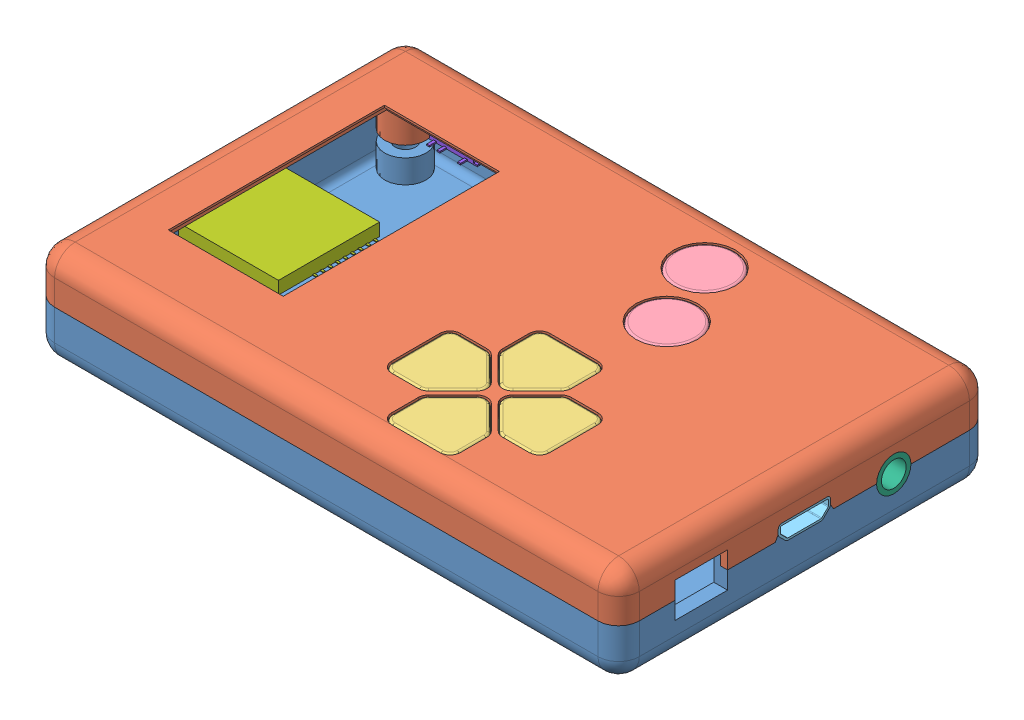
SolidWorks assembly ArduMan, configuration 默认. Lengths in mm.
Overall size (85.3 14.2 54.3).
13 component instances, 8 part files, 24 mates.
Components (placement in the parent):
- ArduMan-bottom-2: ArduMan-bottom [默认] at origin size (85 9.5 54)
- ArduMan-top-3: ArduMan-top [默认] at (0 7.5 0) size (85 7.2 54)
- ArduMan-DPadKey-1: ArduMan-DPadKey [默认] at (4.5 11.2 12.5) size (10.98 3 10.6)
- ArduMan-ABKey-2: ArduMan-ABKey [默认] at (13.5 11.2 -9) size (10 3 10)
- ArduMan-DPadKey-2: ArduMan-DPadKey [默认] at (10 11.2 18) x (0 0 -1) z (1 0 0) size (10.98 3 10.6)
- ArduMan-DPadKey-3: ArduMan-DPadKey [默认] at (15.5 11.2 12.5) x (-1 0 0) z (0 0 -1) size (10.98 3 10.6)
- ArduMan-DPadKey-4: ArduMan-DPadKey [默认] at (10 11.2 7) x (0 0 1) z (-1 0 0) size (10.98 3 10.6)
- ArduMan-ABKey-3: ArduMan-ABKey [默认] at (9.5 11.2 -18.5) x (-1 0 0) z (0 0 -1) size (10 3 10)
- USBMicroF-1: USBMicroF [默认] at (37.44 6.85 0) x (0 0 -1) z (1 0 0) size (7.6 3.5 5.06)
- PJ-313D-1: PJ-313D [默认] at (40 5 -13) x (0 0 -1) z (1 0 0) size (8.4 5.5 14)
- HY-TF1007B-2: HY-TF1007B [默认] at (-25.4 6.85 -6.15) x (0 0 1) z (-1 0 0) size (14.7 2.47 17.6)
- MSK-1103_W13-1: MSK-1103_W13 [默认] at (-38.925 6.85 15.5) x (-1 0 0) z (0 0 -1) size (6.25 1.9 7.8)
- MSK-1103_W13-2: MSK-1103_W13 [默认] at (-31 6.85 -23.425) x (0 0 -1) z (1 0 0) size (6.25 1.9 7.8)
Mates (geometry in assembly coordinates):
- 重合1: coincident anti-aligned: plane of ArduMan-bottom-2 through (0 7.5 0) normal (0 1 0); plane of ArduMan-top-3 through (0 7.5 0) normal (0 -1 0)
- 重合2: coincident aligned: plane of ArduMan-bottom-2 through (-42.5 7.5 27) normal (0 0 1); plane of ArduMan-top-3 through (-42.5 14.2 27) normal (0 0 1)
- 重合3: coincident aligned: plane of ArduMan-bottom-2 through (42.5 7.5 -27) normal (1 0 0); plane of ArduMan-top-3 through (42.5 14.2 -27) normal (1 0 0)
- 重合19: coincident anti-aligned: plane of ArduMan-top-3 through (0 12.2 0) normal (0 -1 0); plane of ArduMan-DPadKey-1 through (0 12.2 16) normal (0 1 0)
- 平行5: parallel aligned: line of ArduMan-top-3 through (-1.5 14.2 9) axis (0 0 1); line of ArduMan-DPadKey-1 through (-1 14.2 9) axis (0 0 1)
- 重合16: coincident aligned: line of ArduMan-top-3 through (4.5 17.4725 12.5) axis (0 -1 0); line of ArduMan-DPadKey-1 through (4.5 14.0504 12.5) axis (0 -1 0)
- 重合22: coincident anti-aligned: plane of ArduMan-top-3 through (0 12.2 0) normal (0 -1 0); plane of ArduMan-ABKey-2 through (13.5 12.2 -9) normal (0 1 0)
- 同心2: concentric anti-aligned: circle of ArduMan-top-3; circle of ArduMan-ABKey-2
- 平行7: parallel aligned: plane of ArduMan-ABKey-2 through (13.5 11.2 -9) normal (0 0 1); plane of assembly through (0 0 0) normal (0 0 1)
- 重合23: coincident aligned: plane of ArduMan-bottom-2 through (42.5 7.5 -27) normal (1 0 0); plane of USBMicroF-1 through (42.5 8.2571 -3.3) normal (1 0 0)
- 重合26: coincident anti-aligned: plane of USBMicroF-1 through (37.44 6.85 0) normal (0 0 -1); plane of assembly through (0 0 0) normal (0 0 1)
- 重合27: coincident aligned: plane of ArduMan-bottom-2 through (42.5 7.5 -27) normal (1 0 0); plane of PJ-313D-1 through (42.5 7.5 -13) normal (1 0 0)
- 平行8: parallel anti-aligned: plane of PJ-313D-1 through (40 5 -13) normal (0 -1 0); plane of assembly through (0 0 0) normal (0 1 0)
- 重合29: coincident aligned: circle of ArduMan-bottom-2; circle of PJ-313D-1
- 重合32: coincident aligned: plane of ArduMan-bottom-2 through (-42.5 7.5 -27) normal (-1 0 0); plane of HY-TF1007B-2 through (-42.5 8.725 400000) normal (-1 0 0)
- 重合37: coincident anti-aligned: plane of HY-TF1007B-2 through (-25.4 6.85 0) normal (0 0 -1); plane of assembly through (0 0 0) normal (0 0 1)
- 重合38: coincident anti-aligned: plane of USBMicroF-1 through (42.5 6.85 2.3929) normal (0 -1 0); plane of assembly through (0 6.85 0) normal (0 1 0)
- 重合39: coincident anti-aligned: plane of HY-TF1007B-2 through (-49.2 6.85 2.0567) normal (0 -1 0); plane of assembly through (0 6.85 0) normal (0 1 0)
- 距离1: distance = 0.3 mm aligned: plane of MSK-1103_W13-1 through (-42.8 6.85 15.5) normal (-1 0 0); plane of ArduMan-bottom-2 through (-42.5 7.5 -27) normal (-1 0 0)
- 重合41: coincident anti-aligned: plane of MSK-1103_W13-1 through (-38.925 6.85 15.5) normal (0 -1 0); plane of assembly through (0 6.85 0) normal (0 1 0)
- 距离2: distance = 15.5 mm anti-aligned: plane of MSK-1103_W13-1 through (-38.925 6.85 15.5) normal (0 0 -1); plane of assembly through (0 0 0) normal (0 0 1)
- 重合42: coincident anti-aligned: plane of MSK-1103_W13-2 through (-31 6.85 -23.425) normal (0 -1 0); plane of assembly through (0 6.85 0) normal (0 1 0)
- 距离3: distance = 0.3 mm aligned: plane of MSK-1103_W13-2 through (-31 6.85 -27.3) normal (0 0 -1); plane of ArduMan-bottom-2 through (-42.5 7.5 -27) normal (0 0 -1)
- 距离4: distance = 11.5 mm anti-aligned: plane of MSK-1103_W13-2 through (-31 6.85 -23.425) normal (1 0 0); plane of ArduMan-bottom-2 through (-42.5 7.5 -27) normal (-1 0 0)
